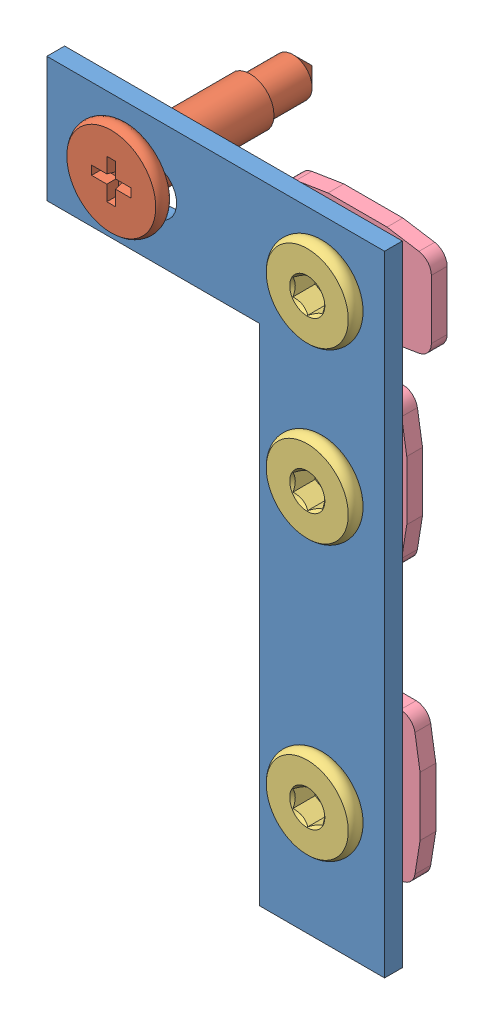
SolidWorks assembly L_BRACKET_ASSEMBLY, configuration Default. Lengths in mm.
Overall size (35.44 63.91 20.62).
8 component instances, 4 part files, 17 mates.
Components (placement in the parent):
- L_BRACKET-1: L_BRACKET [Default] at (11.737 31.6999 49.6565) size (34.29 63.91 1.8)
- Self Tapping Screw-1: Self Tapping Screw [Default] at (17.3402 57.3031 49.6565) x (1 0 0) z (0 -1 0) size (9.6 20.4 9.6)
- LP_SH_SCREW_M5_8mm-1: LP_SH_SCREW_M5_8mm [M5 x 8] at (37.3402 40.1327 41.6565) x (0 0 -1) z (1 0 0) size (9.62 9 9)
- LP_SH_SCREW_M5_8mm-3: LP_SH_SCREW_M5_8mm [M5 x 8] at (37.3402 57.3031 41.6565) x (0 0 -1) z (1 0 0) size (9.62 9 9)
- Tee Nut-1: Tee Nut [Default] at (37.3402 40.1327 46.0531) x (0 -1 0) z (0 0 -1) size (15 10 3)
- Tee Nut-2: Tee Nut [Default] at (37.3402 57.3031 46.0531) x (-1 0 0) z (0 0 -1) size (15 10 3)
- Tee Nut-3: Tee Nut [Default] at (38.6902 13.0373 46.0531) x (0 1 0) z (0 0 -1) size (15 10 3)
- LP_SH_SCREW_M5_8mm-4: LP_SH_SCREW_M5_8mm [M5 x 8] at (37.3402 12.3197 41.6565) x (0 0 -1) z (1 0 0) size (9.62 9 9)
Mates (geometry in assembly coordinates):
- Concentric11: concentric aligned: cylinder of L_BRACKET-1 through (17.3402 57.3031 49.6565) axis (0 0 1) radius 2.5798; cylinder of Self Tapping Screw-1 through (17.3402 57.3031 30.6565) axis (0 0 1) radius 2.425
- Coincident11: coincident anti-aligned: plane of L_BRACKET-1 through (11.737 31.6999 49.6565) normal (0 0 1); plane of Self Tapping Screw-1 through (14.9152 57.3031 49.6565) normal (0 0 -1)
- Concentric21: concentric anti-aligned: cylinder of L_BRACKET-1 through (37.3402 40.1327 49.6565) axis (0 0 1) radius 2.5798; cylinder of LP_SH_SCREW_M5_8mm-1 through (37.3402 40.1327 49.6565) axis (0 0 -1) radius 2.5
- Coincident21: coincident anti-aligned: plane of L_BRACKET-1 through (11.737 31.6999 49.6565) normal (0 0 1); plane of LP_SH_SCREW_M5_8mm-1 through (37.3402 44.2941 49.6565) normal (0 0 -1)
- Concentric41: concentric anti-aligned: cylinder of L_BRACKET-1 through (37.3402 57.3031 49.6565) axis (0 0 1) radius 2.5798; cylinder of LP_SH_SCREW_M5_8mm-3 through (37.3402 57.3031 49.6565) axis (0 0 -1) radius 2.5
- Coincident41: coincident anti-aligned: plane of L_BRACKET-1 through (11.737 31.6999 49.6565) normal (0 0 1); plane of LP_SH_SCREW_M5_8mm-3 through (37.3402 61.4645 49.6565) normal (0 0 -1)
- Concentric5: concentric aligned: cylinder of LP_SH_SCREW_M5_8mm-3 through (37.3402 57.3031 49.6565) axis (0 0 -1) radius 2.5; cylinder of Tee Nut-2 through (37.3402 57.3031 43.0531) axis (0 0 -1) radius 2.1
- Distance1: distance = 1.8 mm anti-aligned: plane of L_BRACKET-1 through (11.737 31.6999 47.8531) normal (0 0 -1); plane of Tee Nut-2 through (31.3402 60.3031 46.0531) normal (0 0 1)
- Parallel1: parallel anti-aligned: plane of L_BRACKET-1 through (11.737 63.6531 47.8531) normal (0 1 0); plane of Tee Nut-2 through (40.3402 52.3031 44.4531) normal (0 -1 0)
- Parallel2: parallel anti-aligned: plane of L_BRACKET-1 through (43.6902 31.6999 47.8531) normal (1 0 0); plane of Tee Nut-1 through (32.3402 43.1327 44.4531) normal (-1 0 0)
- Concentric7: concentric aligned: cylinder of LP_SH_SCREW_M5_8mm-1 through (37.3402 40.1327 49.6565) axis (0 0 -1) radius 2.5; cylinder of Tee Nut-1 through (37.3402 40.1327 43.0531) axis (0 0 -1) radius 2.1
- Distance3: distance = 1.8 mm anti-aligned: plane of L_BRACKET-1 through (11.737 31.6999 47.8531) normal (0 0 -1); plane of Tee Nut-1 through (34.3402 34.1327 46.0531) normal (0 0 1)
- Coincident8: coincident aligned: plane of L_BRACKET-1 through (43.6902 31.6999 47.8531) normal (1 0 0); plane of Tee Nut-3 through (43.6902 10.0373 44.4531) normal (1 0 0)
- Parallel3: parallel anti-aligned: cylinder of L_BRACKET-1 through (37.3402 12.3197 49.6565) axis (0 0 1) radius 2.5798; cylinder of Tee Nut-3 through (38.6902 13.0373 43.0531) axis (0 0 -1) radius 2.1
- Distance4: distance = 1.8 mm anti-aligned: plane of L_BRACKET-1 through (11.737 31.6999 47.8531) normal (0 0 -1); plane of Tee Nut-3 through (41.6902 19.0373 46.0531) normal (0 0 1)
- Concentric91: concentric anti-aligned: cylinder of L_BRACKET-1 through (37.3402 12.3197 49.6565) axis (0 0 1) radius 2.5798; cylinder of LP_SH_SCREW_M5_8mm-4 through (37.3402 12.3197 49.6565) axis (0 0 -1) radius 2.5
- Coincident101: coincident anti-aligned: plane of L_BRACKET-1 through (11.737 31.6999 49.6565) normal (0 0 1); plane of LP_SH_SCREW_M5_8mm-4 through (37.3402 16.4811 49.6565) normal (0 0 -1)
